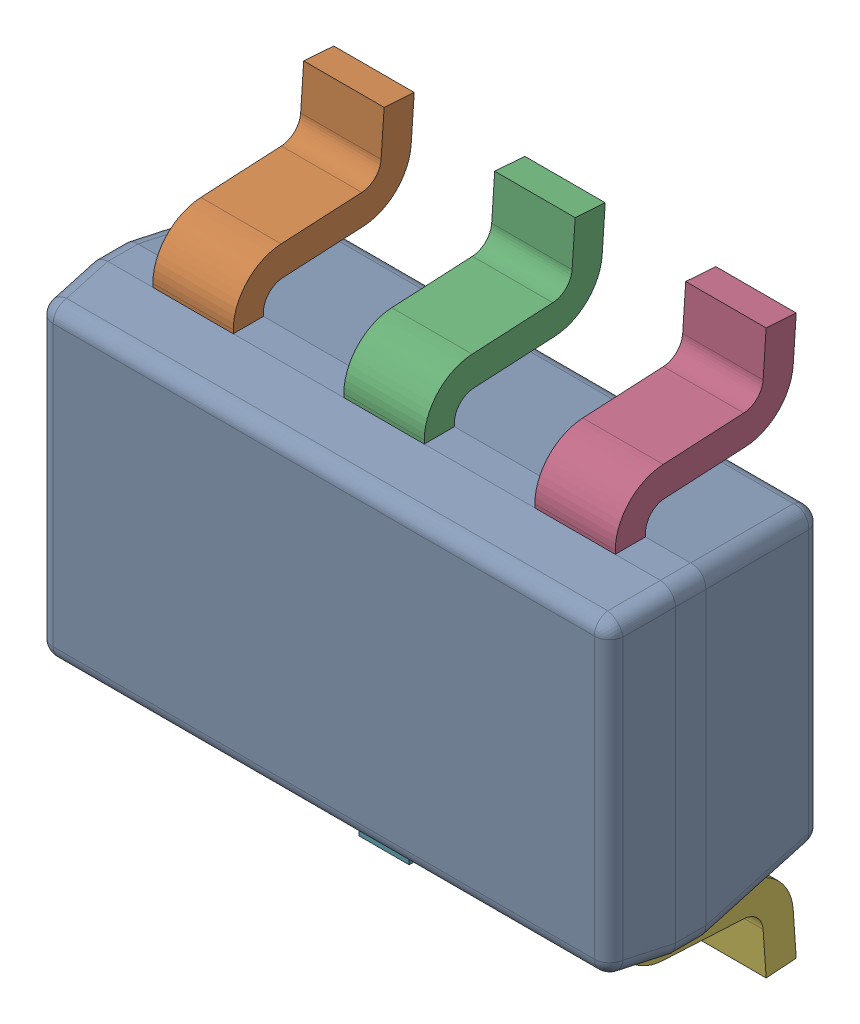
SolidWorks assembly IC4_1.step, configuration Default. Lengths in mm.
Overall size (2.9 2.8 1.2).
8 component instances, 3 part files, 0 mates.
Components (placement in the parent):
- 6348792768_1.step-3: 6348792768_1.step [Default] at (439.713 284.778 0) x (0 -1 0) z (0 0 1) size (2.8 2.9 1.2)
  - BODY-SOT-1213_1.step-3: BODY-SOT-1213_1.step [Default] at (0 0 0.9) x (0 -1 0) z (-1 0 0) size (2.9 1.1 1.6)
  - LEAD-SOT-1214_1.step-21: LEAD-SOT-1214_1.step [Default] at (-0.9395 -0.95 0.25) x (0 -1 0) z (-1 0 0) size (0.4 0.9 0.6)
  - LEAD-SOT-1214_1.step-22: LEAD-SOT-1214_1.step [Default] at (-0.9395 0 0.25) x (0 -1 0) z (-1 0 0) size (0.4 0.9 0.6)
  - LEAD-SOT-1214_1.step-23: LEAD-SOT-1214_1.step [Default] at (-0.9395 0.95 0.25) x (0 -1 0) z (-1 0 0) size (0.4 0.9 0.6)
  - LEAD-SOT-1214_1.step-24: LEAD-SOT-1214_1.step [Default] at (0.9395 -0.95 0.25) x (0 1 0) z (1 0 0) size (0.4 0.9 0.6)
  - LEAD-SOT-1214_1.step-25: LEAD-SOT-1214_1.step [Default] at (0.9395 0.95 0.25) x (0 1 0) z (1 0 0) size (0.4 0.9 0.6)
  - LEAD-DUMMY-1215_1.step-3: LEAD-DUMMY-1215_1.step [Default] at (1.05 0 0.76) x (0 -1 0) z (-1 0 0) size (0.25 0.14 0.25)
